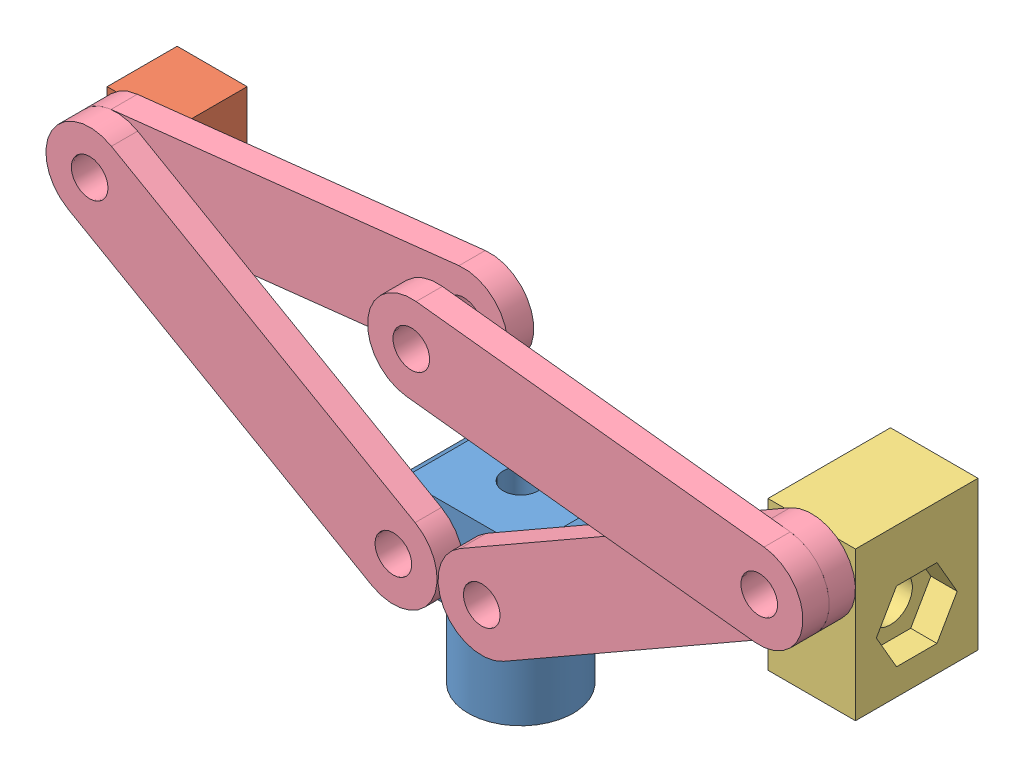
SolidWorks assembly diamond linkage, configuration Default. Lengths in mm.
Overall size (93.16 44.83 20).
7 component instances, 4 part files, 14 mates.
Components (placement in the parent):
- blockbase2-1: blockbase2 [Default] at (-0.4302 1.8013 -4.0998) size (20.18 20 13)
- lockblock-1: lockblock [Default] at (-40.1856 18.6894 -2.0998) size (8 14 8)
- nuttblock2-1: nuttblock2 [Default] at (39.3252 17.1894 -5.0998) size (10 17 14)
- bar-1: bar [Default] at (-22.8329 11.7453 8.9002) x (0.867635 -0.497202 0) z (-0.497202 -0.867635 0) size (50 3 10)
- bar-2: bar [Default] at (21.9725 11.7453 8.9002) x (0.867635 0.497202 0) z (0.497202 -0.867635 0) size (50 3 10)
- bar-3: bar [Default] at (-20.3079 23.8978 8.9002) x (0.993885 0.110423 0) z (-0.110423 0.993885 0) size (50 3 10)
- bar-4: bar [Default] at (19.4475 23.8978 11.9002) x (0.993885 -0.110423 0) z (-0.110423 -0.993885 0) size (50 3 10)
Mates (geometry in assembly coordinates):
- Concentric1: concentric anti-aligned: cylinder of blockbase2-1 through (-5.4802 1.8013 8.9002) axis (0 0 -1) radius 1.65; cylinder of bar-1 through (-5.4802 1.8013 8.9002) axis (0 0 1) radius 2.1
- Concentric2: concentric anti-aligned: cylinder of lockblock-1 through (-40.1856 21.6894 5.9002) axis (0 0 -1) radius 1.6; cylinder of bar-1 through (-40.1856 21.6894 8.9002) axis (0 0 1) radius 2.1
- Coincident1: coincident anti-aligned: plane of blockbase2-1 through (-4.9302 1.8013 8.9002) normal (0 0 1); plane of bar-1 through (-40.1856 21.6894 8.9002) normal (0 0 -1)
- Concentric3: concentric anti-aligned: cylinder of blockbase2-1 through (4.6198 1.8013 8.9002) axis (0 0 -1) radius 1.65; cylinder of bar-2 through (4.6198 1.8013 8.9002) axis (0 0 1) radius 2.1
- Coincident3: coincident anti-aligned: plane of blockbase2-1 through (-4.9302 1.8013 8.9002) normal (0 0 1); plane of bar-2 through (4.6198 1.8013 8.9002) normal (0 0 -1)
- Coincident4: coincident anti-aligned: plane of nuttblock2-1 through (34.3252 25.6894 8.9002) normal (0 0 1); plane of bar-2 through (4.6198 1.8013 8.9002) normal (0 0 -1)
- Concentric4: concentric anti-aligned: cylinder of nuttblock2-1 through (39.3252 21.6894 8.9002) axis (0 0 -1) radius 1.6; cylinder of bar-2 through (39.3252 21.6894 8.9002) axis (0 0 1) radius 2.1
- Perpendicular1: perpendicular: line of lockblock-1 through (-44.1856 25.6894 5.9002) axis (0 -1 0); plane of assembly
- Concentric10: concentric aligned: cylinder of lockblock-1 through (-36.1856 15.6894 1.9002) axis (-1 0 0) radius 2.5; cylinder of nuttblock2-1 through (44.3252 15.6894 1.9002) axis (-1 0 0) radius 2.5
- Concentric11: concentric anti-aligned: cylinder of bar-1 through (-40.1856 21.6894 8.9002) axis (0 0 1) radius 2.1; cylinder of bar-3 through (-40.1856 21.6894 8.9002) axis (0 0 -1) radius 2.1
- Coincident9: coincident anti-aligned: plane of bar-1 through (-40.1856 21.6894 8.9002) normal (0 0 -1); plane of bar-3 through (-40.1856 21.6894 8.9002) normal (0 0 1)
- Concentric12: concentric anti-aligned: circle of bar-2; cylinder of bar-4 through (39.3252 21.6894 11.9002) axis (0 0 1) radius 2.1
- Coincident11: coincident anti-aligned: plane of bar-2 through (4.6198 1.8013 11.9002) normal (0 0 1); plane of bar-4 through (-0.4302 26.1063 11.9002) normal (0 0 -1)
- Concentric13: concentric anti-aligned: cylinder of bar-3 through (-0.4302 26.1063 8.9002) axis (0 0 -1) radius 2.1; cylinder of bar-4 through (-0.4302 26.1063 11.9002) axis (0 0 1) radius 2.1
